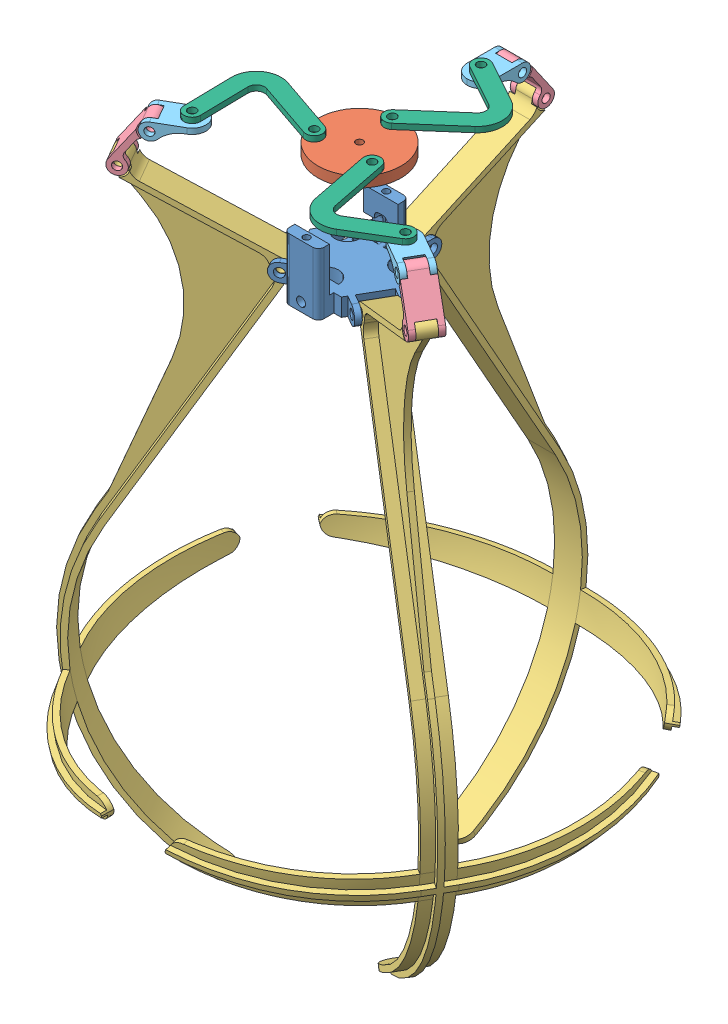
SolidWorks assembly AssiemeTotaledef, configuration Default. Lengths in mm.
Overall size (341.08 245.95 295.62).
15 component instances, 7 part files, 32 mates.
Components (placement in the parent):
- basedef-1: basedef [Default] at (-17.2567 -4.4199 46.9012) size (250 217.42 250)
- ServoDiscDef-1: ServoDiscDef [Default] at (-17.2567 38.2612 46.9012) x (-0.009213 0 -0.999958) z (0 -1 0) size (30 30 3.78)
- Parte1^AssiemeTotaledef-1: Parte1^AssiemeTotaledef [Default] at origin (virtual)
- Braccetto-1: Braccetto [Default] at (-22.5567 -1.2199 27.6127) x (1 0 0) z (0 0.581934 0.813236) size (130.99 200.98 140.58)
- Giunzione-1: Giunzione [Default] at (-22.5567 10.132 -14.7279) x (0 -0.821114 -0.570764) z (1 0 0) size (21 6 10)
- Giunzionina-1: Giunzionina [Default] at (-22.5567 35.5862 4.4611) x (0 0 -1) z (1 0 0) size (18 6 10)
- L-1: L [Default] at (-15.6588 40.2612 12.2619) x (0.489529 0 -0.871987) z (0 -1 0) size (34.2 29.48 2)
- Braccetto-2: Braccetto [Default] at (-31.311 -1.2199 61.1353) x (-0.5 0 -0.866025) z (0.704283 0.581934 -0.406618) size (130.99 200.98 140.58)
- Braccetto-3: Braccetto [Default] at (2.0976 -1.2199 51.9554) x (-0.5 0 0.866025) z (-0.704283 0.581934 -0.406618) size (130.99 200.98 140.58)
- L-2: L [Default] at (11.9428 40.2612 65.6046) x (0.510399 0 0.859938) z (0 -1 0) size (34.2 29.48 2)
- L-3: L [Default] at (-48.0542 40.2612 62.8369) x (-0.999927 0 0.012049) z (0 -1 0) size (34.2 29.48 2)
- Giunzione-2: Giunzione [Default] at (-67.979 10.132 82.3056) x (-0.494296 -0.821114 0.285382) z (-0.5 0 -0.866025) size (21 6 10)
- Giunzione-3: Giunzione [Default] at (38.7656 10.132 73.1257) x (0.494296 -0.821114 0.285382) z (-0.5 0 0.866025) size (21 6 10)
- Giunzionina-2: Giunzionina [Default] at (-51.3609 35.5862 72.7111) x (-0.866025 0 0.5) z (-0.5 0 -0.866025) size (18 6 10)
- Giunzionina-3: Giunzionina [Default] at (22.1475 35.5862 63.5313) x (0.866025 0 0.5) z (-0.5 0 0.866025) size (18 6 10)
Mates (geometry in assembly coordinates):
- centro1: concentric: line of basedef-1 through (-17.2567 -4.7399 46.9012) axis (0 1 0); circle of ServoDiscDef-1
- Distanza1: distance = 32.5 mm: plane of basedef-1 through (-17.2567 1.9801 46.9012) normal (0 1 0); plane of ServoDiscDef-1 through (-17.2567 34.4801 46.9012) normal (0 -1 0)
- Concentrico1: concentric: cylinder of basedef-1 through (8.4462 -1.2199 27.6127) axis (-1 0 0) radius 1.625; cylinder of Braccetto-1 through (-22.5567 -1.2199 27.6127) axis (1 0 0) radius 1.5
- Coincidente26: coincident: plane of basedef-1 through (-22.5567 1.9801 24.4127) normal (1 0 0); plane of Braccetto-1 through (-22.5567 22.9445 -15.9466) normal (-1 0 0)
- Coincidente27: coincident: plane of ServoDiscDef-1 through (-17.2567 38.2612 46.9012) normal (0 1 0); plane of L-1 through (-17.5567 38.2612 2.6148) normal (0 -1 0)
- Concentrico6: concentric: cylinder of Giunzionina-1 through (-17.5567 28.2612 2.6148) axis (0 1 0) radius 1.5; cylinder of L-1 through (-17.5567 40.2612 2.6148) axis (0 -1 0) radius 1.5
- Concentrico7: concentric: cylinder of ServoDiscDef-1 through (-17.3673 38.2612 34.9017) axis (0 -1 0) radius 1.625; circle of L-1
- Coincidente28: coincident: plane of Giunzionina-1 through (-12.5567 38.2612 7.6148) normal (0 1 0); plane of L-1 through (-17.5567 38.2612 2.6148) normal (0 -1 0)
- Concentrico8: concentric: cylinder of Giunzione-1 through (-12.5567 35.2612 -7.3852) axis (-1 0 0) radius 1.5; cylinder of Giunzionina-1 through (-22.5567 35.2612 -7.3852) axis (1 0 0) radius 1.5
- Coincidente29: coincident: plane of Giunzione-1 through (-20.5567 35.2612 -7.3852) normal (-1 0 0); plane of Giunzionina-1 through (-20.5567 35.2612 -7.3852) normal (1 0 0)
- Coincidente31: coincident: plane of Braccetto-1 through (-20.5567 22.9445 -15.9466) normal (-1 0 0); plane of Giunzione-1 through (-20.5567 22.9445 -15.9466) normal (1 0 0)
- Concentrico10: concentric: cylinder of Braccetto-1 through (-22.5567 22.9445 -15.9466) axis (1 0 0) radius 1.5; cylinder of Giunzione-1 through (-12.5567 22.9445 -15.9466) axis (-1 0 0) radius 1.5
- Concentrico12: concentric: cylinder of basedef-1 through (-20.7039 -1.2199 91.4487) axis (0.5 0 -0.866025) radius 1.625; cylinder of Braccetto-3 through (2.0976 -1.2199 51.9554) axis (-0.5 0 0.866025) radius 1.5
- Coincidente34: coincident: plane of basedef-1 through (4.8689 1.9801 53.5554) normal (-0.5 0 0.866025); plane of Braccetto-3 through (39.8211 22.9445 73.7351) normal (0.5 0 -0.866025)
- Coincidente35: coincident: plane of basedef-1 through (-34.0823 1.9801 62.7353) normal (-0.5 0 -0.866025); plane of Braccetto-2 through (-69.0345 22.9445 82.915) normal (0.5 0 0.866025)
- Concentrico13: concentric: cylinder of basedef-1 through (-39.9091 -1.2199 46.243) axis (0.5 0 0.866025) radius 1.625; cylinder of Braccetto-2 through (-31.311 -1.2199 61.1353) axis (-0.5 0 -0.866025) radius 1.5
- Concentrico15: concentric: cylinder of ServoDiscDef-1 through (-27.5933 38.2612 52.9966) axis (0 -1 0) radius 1.625; cylinder of L-3 through (-27.5933 40.2612 52.9966) axis (0 -1 0) radius 1.5
- Concentrico16: concentric: cylinder of ServoDiscDef-1 through (-6.8096 38.2612 52.8051) axis (0 -1 0) radius 1.625; cylinder of L-2 through (-6.8096 40.2612 52.8051) axis (0 -1 0) radius 1.5
- Coincidente36: coincident: plane of ServoDiscDef-1 through (-17.2567 38.2612 46.9012) normal (0 1 0); plane of L-3 through (-55.4598 38.2612 69.3041) normal (0 -1 0)
- Coincidente37: coincident: plane of ServoDiscDef-1 through (-17.2567 38.2612 46.9012) normal (0 1 0); plane of L-2 through (21.2464 38.2612 68.7845) normal (0 -1 0)
- Coincidente38: coincident: plane of L-3 through (-55.4598 38.2612 69.3041) normal (0 -1 0); plane of Giunzionina-2 through (-53.6297 38.2612 62.474) normal (0 1 0)
- Coincidente39: coincident: plane of L-2 through (21.2464 38.2612 68.7845) normal (0 -1 0); plane of Giunzionina-3 through (14.4163 38.2612 70.6146) normal (0 1 0)
- Concentrico17: concentric: cylinder of L-2 through (21.2464 40.2612 68.7845) axis (0 -1 0) radius 1.5; circle of Giunzionina-3
- Concentrico18: concentric: cylinder of L-3 through (-55.4598 40.2612 69.3041) axis (0 -1 0) radius 1.5; cylinder of Giunzionina-2 through (-55.4598 28.2612 69.3041) axis (0 1 0) radius 1.5
- Concentrico20: concentric: circle of Giunzione-3; circle of Giunzionina-3
- Concentrico21: concentric: circle of Giunzione-2; cylinder of Giunzionina-2 through (-61.62 35.2612 78.6343) axis (-0.5 0 -0.866025) radius 1.5
- Coincidente40: coincident: plane of Giunzione-2 through (-62.62 35.2612 76.9022) normal (0.5 0 0.866025); plane of Giunzionina-2 through (-62.62 35.2612 76.9022) normal (-0.5 0 -0.866025)
- Coincidente41: coincident: plane of Giunzione-3 through (31.4066 35.2612 71.1864) normal (0.5 0 -0.866025); plane of Giunzionina-3 through (31.4066 35.2612 71.1864) normal (-0.5 0 0.866025)
- Concentrico22: concentric: circle of Braccetto-3; circle of Giunzione-3
- Coincidente42: coincident: plane of Braccetto-3 through (38.8211 22.9445 75.4672) normal (0.5 0 -0.866025); plane of Giunzione-3 through (38.8211 22.9445 75.4672) normal (-0.5 0 0.866025)
- Concentrico23: concentric: cylinder of Braccetto-2 through (-69.0345 22.9445 82.915) axis (-0.5 0 -0.866025) radius 1.5; cylinder of Giunzione-2 through (-74.0345 22.9445 74.2547) axis (0.5 0 0.866025) radius 1.5
- Coincidente43: coincident: plane of Braccetto-2 through (-73.0345 22.9445 75.9868) normal (-0.5 0 -0.866025); plane of Giunzione-2 through (-73.0345 22.9445 75.9868) normal (0.5 0 0.866025)
